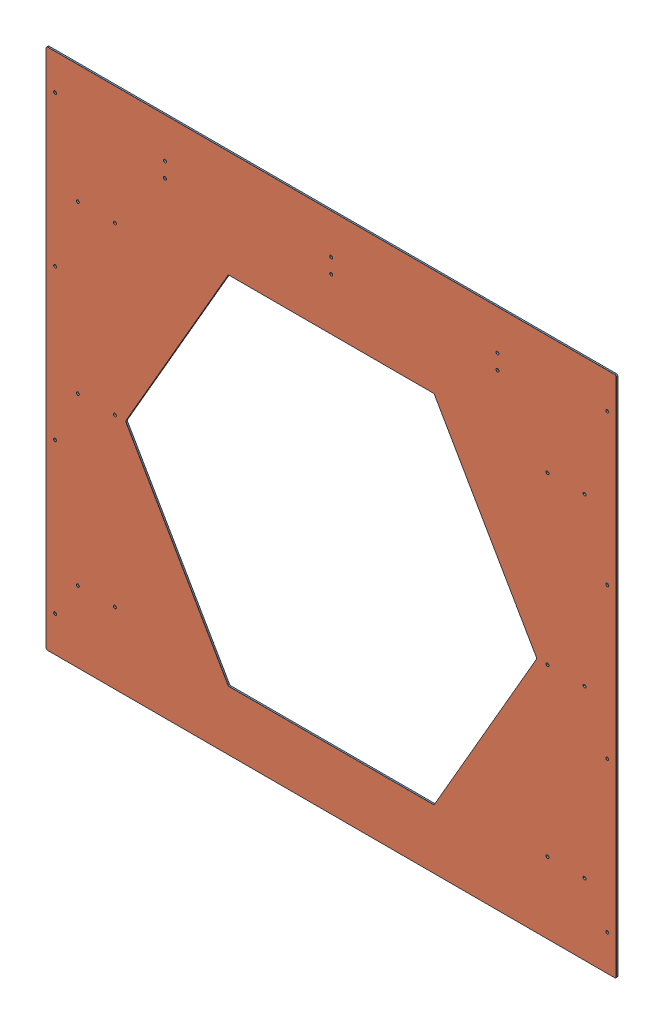
SolidWorks assembly GE-20320, configuration GE-20320-Red. Lengths in mm.
Overall size (1219.2 1117.6 3.43).
2 component instances, 2 part files, 6 mates.
Components (placement in the parent):
- GE-20306-1: GE-20306 [Default] at (609.6 1016 -3.175) x (-1 0 0) z (0 0 1) size (1219.2 1117.6 3.17)
- GE-20320-Vinyl-1: GE-20320-Vinyl [GE-20320-Red-Vinyl] at (609.6 0 0.254) size (1219.2 1117.6 0.25)
Mates (geometry in assembly coordinates):
- Coincident1: coincident anti-aligned: plane of GE-20306-1 through (609.6 0 0) normal (0 -1 0)
- Coincident2: coincident aligned: plane of GE-20306-1 through (609.6 1016 0) normal (0 0 1)
- Symmetric1: symmetric aligned: plane of GE-20306-1 through (609.6 1016 0) normal (1 0 0); plane of GE-20306-1 through (-609.6 1016 0) normal (-1 0 0)
- Coincident3: coincident anti-aligned: plane of GE-20306-1 through (609.6 1016 0) normal (0 0 1); plane of GE-20320-Vinyl-1 through (-609.6 1117.6 0) normal (0 0 -1)
- Coincident4: coincident aligned: plane of GE-20306-1 through (609.6 1016 0) normal (1 0 0); plane of GE-20320-Vinyl-1 through (609.6 1016 0.254) normal (1 0 0)
- Coincident5: coincident aligned: plane of GE-20306-1 through (609.6 0 0) normal (0 -1 0); plane of GE-20320-Vinyl-1 through (609.6 0 0.254) normal (0 -1 0)
